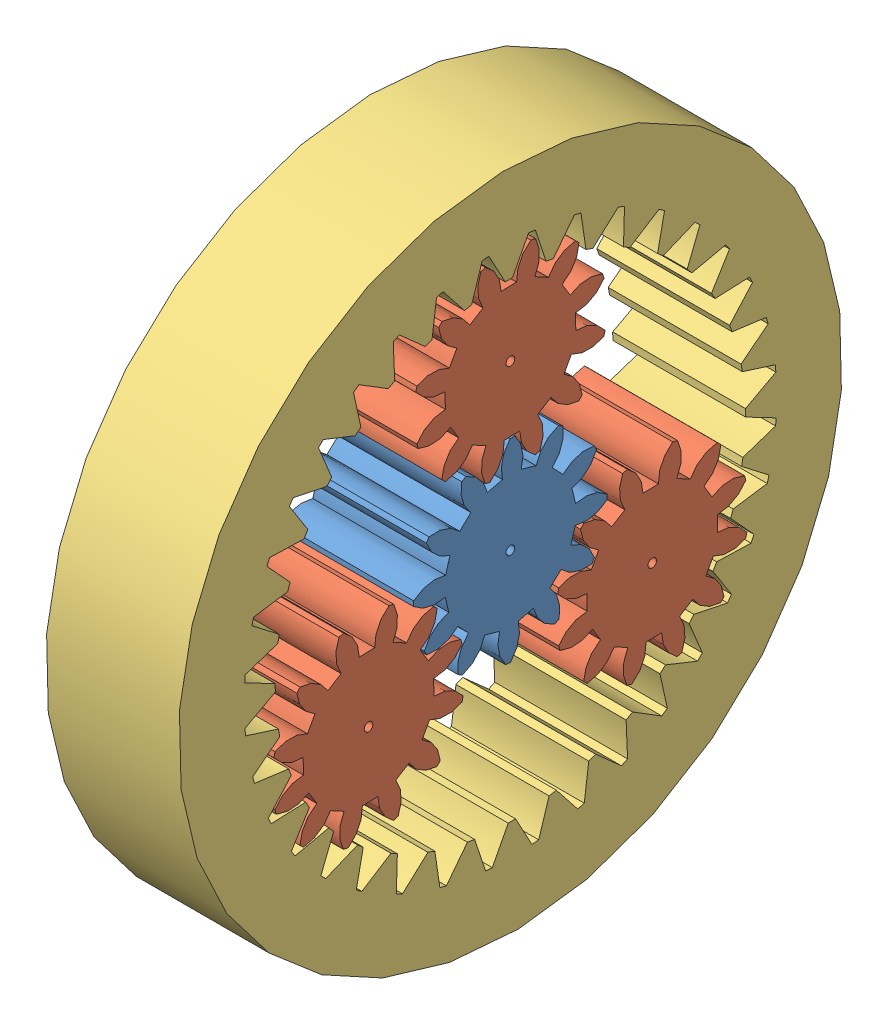
SolidWorks assembly Assem1, configuration Default. Lengths in mm.
Overall size (12 83.47 83.47).
5 component instances, 3 part files, 14 mates.
Components (placement in the parent):
- Sun - Metric - Spur gear 1.25M 12T 20PA 12FW ---S12N75H50L0.8N-1: Sun - Metric - Spur gear 1.25M 12T 20PA 12FW ---S12N75H50L0.8N [Metric - Spur gear 1.25M 12T 20PA 12FW ---S12N75H50L0.8N] at (-12 0 0) x (1 0 0) z (0 0.280567 0.959834) size (12 17.01 17.01)
- Planet - Metric - Spur gear 1.25M 12T 20PA 12FW ---S12N75H50L0.8N-1: Planet - Metric - Spur gear 1.25M 12T 20PA 12FW ---S12N75H50L0.8N [Metric - Spur gear 1.25M 12T 20PA 12FW ---S12N75H50L0.8N] at (-12 14.8 0) x (1 0 0) z (0 -0.023695 0.999719) size (12 17.01 17.01)
- Planet - Metric - Spur gear 1.25M 12T 20PA 12FW ---S12N75H50L0.8N-5: Planet - Metric - Spur gear 1.25M 12T 20PA 12FW ---S12N75H50L0.8N [Metric - Spur gear 1.25M 12T 20PA 12FW ---S12N75H50L0.8N] at (-12 -7.4 -12.8172) x (1 0 0) z (0 -0.023695 0.999719) size (12 17.01 17.01)
- Planet - Metric - Spur gear 1.25M 12T 20PA 12FW ---S12N75H50L0.8N-6: Planet - Metric - Spur gear 1.25M 12T 20PA 12FW ---S12N75H50L0.8N [Metric - Spur gear 1.25M 12T 20PA 12FW ---S12N75H50L0.8N] at (-12 -7.4 12.8172) x (1 0 0) z (0 -0.023695 0.999719) size (12 17.01 17.01)
- Ring - Metric - Internal spur gear 1.25M 36T 20PA 12FW ---S36S60OD 1AF-1: Ring - Metric - Internal spur gear 1.25M 36T 20PA 12FW ---S36S60OD 1AF [Metric - Internal spur gear 1.25M 36T 20PA 12FW ---S36S60OD 1AF] at (-12 0 0) x (1 0 0) z (0 0.822821 -0.568301) size (12 60 60)
Mates (geometry in assembly coordinates):
- Concentric3: concentric anti-aligned: cylinder of Sun - Metric - Spur gear 1.25M 12T 20PA 12FW ---S12N75H50L0.8N-1 through (38.0001 0 0) axis (-1 0 0) radius 0.4; line of assembly
- Coincident5: coincident aligned: plane of Sun - Metric - Spur gear 1.25M 12T 20PA 12FW ---S12N75H50L0.8N-1 through (0 0 0) normal (1 0 0); plane of assembly through (0 0 0) normal (1 0 0)
- Concentric4: concentric anti-aligned: cylinder of Planet - Metric - Spur gear 1.25M 12T 20PA 12FW ---S12N75H50L0.8N-1 through (38.0001 14.8 0) axis (-1 0 0) radius 0.4; line of assembly
- Coincident7: coincident aligned: plane of Sun - Metric - Spur gear 1.25M 12T 20PA 12FW ---S12N75H50L0.8N-1 through (0 0 0) normal (1 0 0); plane of Planet - Metric - Spur gear 1.25M 12T 20PA 12FW ---S12N75H50L0.8N-1 through (0 14.8 0) normal (1 0 0)
- Concentric5: concentric anti-aligned: cylinder of Planet - Metric - Spur gear 1.25M 12T 20PA 12FW ---S12N75H50L0.8N-5 through (38.0001 -7.4 -12.8172) axis (-1 0 0) radius 0.4; line of assembly
- Coincident9: coincident aligned: plane of Sun - Metric - Spur gear 1.25M 12T 20PA 12FW ---S12N75H50L0.8N-1 through (0 0 0) normal (1 0 0); plane of Planet - Metric - Spur gear 1.25M 12T 20PA 12FW ---S12N75H50L0.8N-5 through (0 -7.4 -12.8172) normal (1 0 0)
- Concentric6: concentric anti-aligned: cylinder of Planet - Metric - Spur gear 1.25M 12T 20PA 12FW ---S12N75H50L0.8N-6 through (38.0001 -7.4 12.8172) axis (-1 0 0) radius 0.4; line of assembly
- Coincident11: coincident aligned: plane of Sun - Metric - Spur gear 1.25M 12T 20PA 12FW ---S12N75H50L0.8N-1 through (0 0 0) normal (1 0 0); plane of Planet - Metric - Spur gear 1.25M 12T 20PA 12FW ---S12N75H50L0.8N-6 through (0 -7.4 12.8172) normal (1 0 0)
- Concentric7: concentric anti-aligned: cylinder of Ring - Metric - Internal spur gear 1.25M 36T 20PA 12FW ---S36S60OD 1AF-1 through (-22 0 0) axis (-1 0 0) radius 30; line of assembly
- Coincident13: coincident aligned: plane of Sun - Metric - Spur gear 1.25M 12T 20PA 12FW ---S12N75H50L0.8N-1 through (0 0 0) normal (1 0 0); plane of Ring - Metric - Internal spur gear 1.25M 36T 20PA 12FW ---S36S60OD 1AF-1 through (0 -17.4849 12.0764) normal (1 0 0)
- GearMate1: gear = 0.8 : 0.8 mm: cylinder of Planet - Metric - Spur gear 1.25M 12T 20PA 12FW ---S12N75H50L0.8N-6 through (38.0001 -7.4 12.8172) axis (-1 0 0) radius 0.4; cylinder of Sun - Metric - Spur gear 1.25M 12T 20PA 12FW ---S12N75H50L0.8N-1 through (38.0001 0 0) axis (-1 0 0) radius 0.4
- GearMate2: gear = 0.8 : 0.8 mm: cylinder of Planet - Metric - Spur gear 1.25M 12T 20PA 12FW ---S12N75H50L0.8N-1 through (38.0001 14.8 0) axis (-1 0 0) radius 0.4; cylinder of Sun - Metric - Spur gear 1.25M 12T 20PA 12FW ---S12N75H50L0.8N-1 through (38.0001 0 0) axis (-1 0 0) radius 0.4
- GearMate3: gear = 0.8 : 0.8 mm: cylinder of Planet - Metric - Spur gear 1.25M 12T 20PA 12FW ---S12N75H50L0.8N-5 through (38.0001 -7.4 -12.8172) axis (-1 0 0) radius 0.4; cylinder of Sun - Metric - Spur gear 1.25M 12T 20PA 12FW ---S12N75H50L0.8N-1 through (38.0001 0 0) axis (-1 0 0) radius 0.4
- GearMate4: gear = 3 : 1 mm: cylinder of Planet - Metric - Spur gear 1.25M 12T 20PA 12FW ---S12N75H50L0.8N-1 through (38.0001 14.8 0) axis (-1 0 0) radius 0.4; cylinder of Ring - Metric - Internal spur gear 1.25M 36T 20PA 12FW ---S36S60OD 1AF-1 through (-22 0 0) axis (-1 0 0) radius 30
